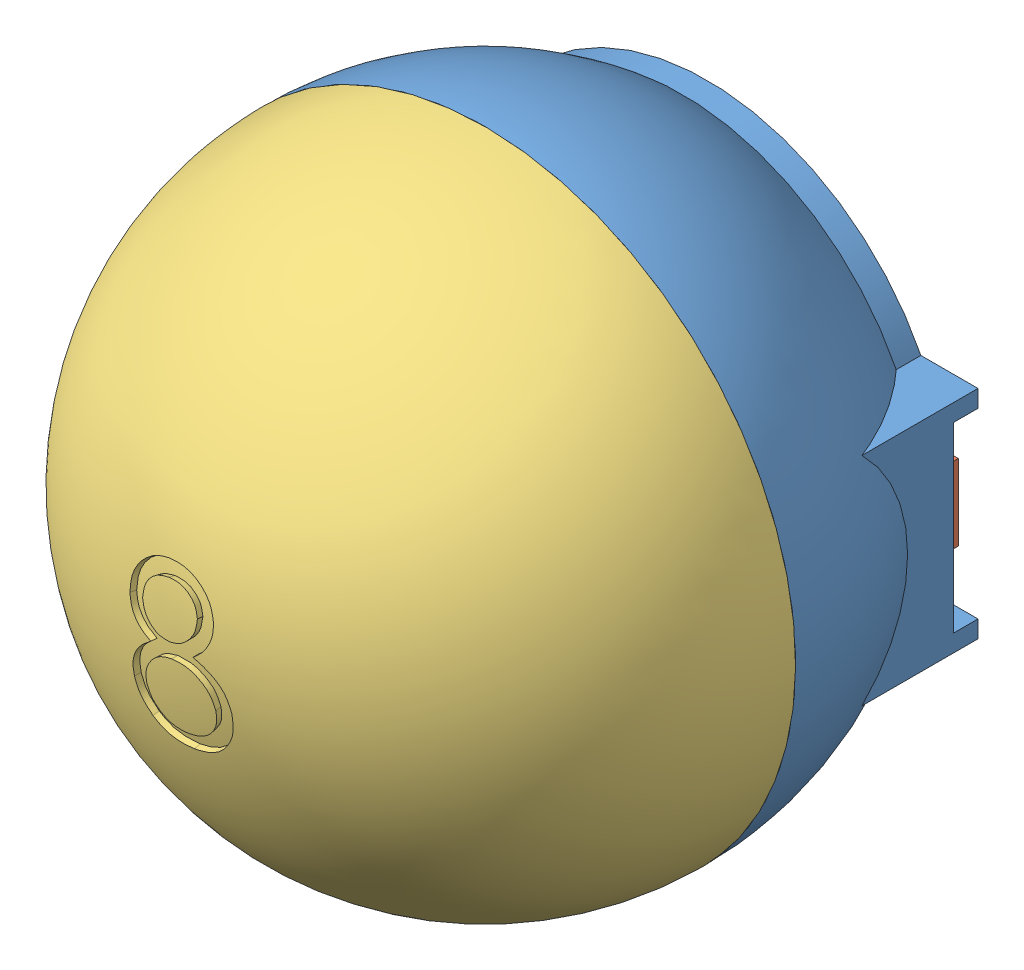
SolidWorks assembly WiFiKit_8ball, configuration Default. Lengths in mm.
Overall size (87.74 87.74 54).
17 component instances, 12 part files, 18 mates.
Components (placement in the parent):
- Front Half-1: Front Half [Default] at origin size (63 63 22.5)
- Heltek_Kit8-1: Heltek_Kit8 [Default] at (-25.5 0 -18.5) x (1 0 0) z (0 1 0) size (51 8 18.5)
- Back Half-1: Back Half [Default] x (-0.573576 -0.819152 0) z (0 0 -1) size (63 63 34.5)
- switch_full_assy-1: switch_full_assy [Default] at (17.2022 -12.0451 9) x (0 0 -1) z (-0.819152 0.573576 0) size (29.31 25 47.01)
  - Micro Switch with Lever open-2: Micro Switch with Lever open [Default] at origin size (13.35 5.81 12.8)
  - Base_skewed2-1: Base_skewed2 [Default] at (-3.2499 4 1.469) x (0.999989 0 0.004762) z (0 -1 0) size (11.45 20 3.6)
  - base_skewed1-2: base_skewed1 [Default] at (-3.2499 4 1.469) x (0.999989 0 0.004762) z (0 -1 0) size (11.45 20 6.9)
  - Lever_Battery_tang-1: Lever_Battery_tang [350mah] at (3.2 2.7 11.9999) x (0.821874 0 -0.569669) z (0 -1 0) size (9.5 35.75 25)
  - M2 x 0.4mm Thread 10mm LONG SOCKET HEAD CAP SCREW.step-1: M2 x 0.4mm Thread 10mm LONG SOCKET HEAD CAP SCREW.step [Default] at (-3.2499 6 1.469) x (0.040459 0 -0.999181) z (0 1 0) size (3.8 3.8 12)
  - M2 x 0.4mm Thread HEX NUT.step-1: M2 x 0.4mm Thread HEX NUT.step [Default] at (-3.2499 4.8 1.469) x (0.999181 0 0.040459) z (0 -1 0) size (4.62 4.63 1.61)
  - M2 x 0.4mm Thread 10mm LONG SOCKET HEAD CAP SCREW.step-2: M2 x 0.4mm Thread 10mm LONG SOCKET HEAD CAP SCREW.step [Default] at (3.25 6 1.5) x (1 0 0) z (0 1 0) size (3.8 3.8 12)
  - M2 x 0.4mm Thread 10mm LONG SOCKET HEAD CAP SCREW.step-3: M2 x 0.4mm Thread 10mm LONG SOCKET HEAD CAP SCREW.step [Default] at (3.2 6 11.9999) x (1 0 0) z (0 1 0) size (3.8 3.8 12)
  - M2 x 0.4mm Thread HEX NUT.step-2: M2 x 0.4mm Thread HEX NUT.step [Default] at (3.2 4.8 11.9999) x (-0.713843 0 -0.700306) z (0 1 0) size (4.62 4.63 1.61)
  - M2 x 0.4mm Thread HEX NUT.step-3: M2 x 0.4mm Thread HEX NUT.step [Default] at (3.25 4.8 1.5) x (0.713843 0 0.700306) z (0 1 0) size (4.62 4.63 1.61)
- 5mmNeopixelLED^WiFiKit_8ball-1: 5mmNeopixelLED^WiFiKit_8ball [Default] at (-10 -15 -13) x (0 -1 0) z (1 0 0) size (5.9 12 5.45) (virtual)
- PushButtonSwitch^WiFiKit_8ball-1: PushButtonSwitch^WiFiKit_8ball [Default] at (0 -15 -9.5) x (1 0 0) z (0 1 0) size (9.5 27.5 9.5) (virtual)
- 350mahBattery-1: 350mahBattery [Default] at (-5.8857 4.1212 -4.2018) x (0.573576 0.819152 0) z (0.67324 -0.471408 0.569669) size (36 6 20)
Mates (geometry in assembly coordinates):
- Distance1: distance = 20 mm anti-aligned: plane of Heltek_Kit8-1 through (-25.5 0 -20) normal (0 0 -1)
- Distance2: distance = 25.5 mm: plane of assembly through (0 0 0) normal (1 0 0); plane of assembly; plane of Heltek_Kit8-1 through (-25.5 0 -18.5) normal (1 0 0)
- Distance5: distance = 0 mm aligned: plane of Heltek_Kit8-1 through (-25.5 0 -18.5) normal (0 1 0); plane of Front Half-1 through (0 0 0) normal (0 1 0)
- Concentric1: concentric aligned: cylinder of Front Half-1 through (0 0 -3) axis (0 0 1) radius 30.75; cylinder of Back Half-1 through (0 0 -3) axis (0 0 1) radius 30.75
- Coincident1: coincident anti-aligned: plane of Front Half-1 through (0 0 0) normal (0 0 1); plane of Back Half-1 through (0 0 0) normal (0 0 -1)
- Coincident10: coincident aligned: plane of Back Half-1 through (0 0 0) normal (-0.573576 -0.819152 0); plane of switch_full_assy-1 through (17.2022 -12.0451 9) normal (-0.573576 -0.819152 0)
- Angle2: planar angle = 2.181662 rad aligned: plane of Back Half-1 through (0 0 0) normal (-0.573576 -0.819152 0)
- Distance11: distance = 21 mm aligned: plane of switch_full_assy-1 through (17.2022 -12.0451 9) normal (-0.819152 0.573576 0); plane of Back Half-1 through (0 0 0) normal (-0.819152 0.573576 0)
- Distance12: distance = 9 mm aligned: plane of switch_full_assy-1 through (17.2022 -12.0451 9) normal (0 0 -1); plane of Back Half-1 through (0 0 0) normal (0 0 -1)
- Concentric2: concentric anti-aligned: cylinder of Front Half-1 through (-10 -15 0) axis (0 0 -1) radius 2.5; cylinder of 5mmNeopixelLED^WiFiKit_8ball-1 through (-10 -15 -21) axis (0 0 1) radius 2.5
- Coincident16: coincident anti-aligned: plane of Front Half-1 through (-10 -15 -13) normal (0 0 1); plane of 5mmNeopixelLED^WiFiKit_8ball-1 through (-10 -15 -13) normal (0 0 -1)
- Parallel2: parallel anti-aligned: plane of Front Half-1 through (-26 9.5 0) normal (1 0 0); plane of 5mmNeopixelLED^WiFiKit_8ball-1 through (-12.5 -13.434 11.4659) normal (-1 0 0)
- Concentric3: concentric anti-aligned: cylinder of Front Half-1 through (0 -15 0) axis (0 0 -1) radius 3.4; cylinder of PushButtonSwitch^WiFiKit_8ball-1 through (0 -15 -16) axis (0 0 1) radius 3.43
- Distance13: distance = 1.5 mm anti-aligned: plane of Front Half-1 through (0 -15 -11) normal (0 0 1); plane of PushButtonSwitch^WiFiKit_8ball-1 through (0 -15 -9.5) normal (0 0 -1)
- Parallel3: parallel anti-aligned: plane of Front Half-1 through (-26 9.5 0) normal (1 0 0); plane of PushButtonSwitch^WiFiKit_8ball-1 through (-1.85 -13.9 5) normal (-1 0 0)
- Coincident19: coincident anti-aligned: plane of switch_full_assy-1/Lever_Battery_tang-1 through (6.8832 -1.5846 5.3166) normal (-0.466646 0.326749 0.821874); plane of 350mahBattery-1 through (-5.8857 4.1212 -4.2018) normal (0.466646 -0.326749 -0.821874)
- Coincident20: coincident anti-aligned: plane of switch_full_assy-1 through (17.2022 -12.0451 9) normal (-0.573576 -0.819152 0); plane of 350mahBattery-1 through (-5.8857 4.1212 -4.2018) normal (0.573576 0.819152 0)
- Coincident21: coincident anti-aligned: plane of switch_full_assy-1/Lever_Battery_tang-1 through (-9.7223 18.9301 -4.9673) normal (0.67324 -0.471408 0.569669); plane of 350mahBattery-1 through (-25.7424 -3.9489 -4.9673) normal (-0.67324 0.471408 -0.569669)
